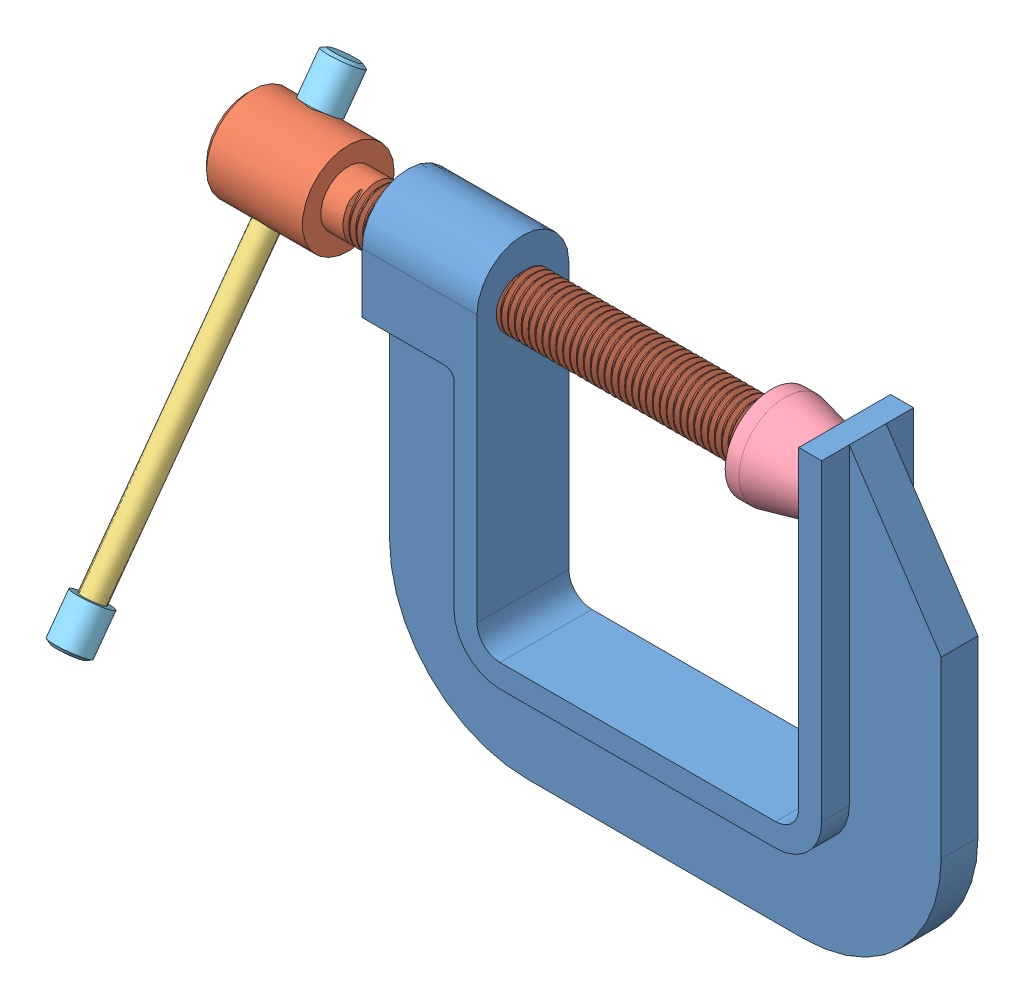
SolidWorks assembly Assem1, configuration Default. Lengths in mm.
Overall size (206.43 104.53 68.23).
6 component instances, 5 part files, 13 mates.
Components (placement in the parent):
- 1-Clamp-1: 1-Clamp [Default] at (98.6392 5.6891 70.0698) size (120.62 98 20)
- 2-Screw-1: 2-Screw [Default] at (62.5202 91.6472 70.0698) x (1 0 0) z (0 0.589813 0.80754) size (206.43 20 20)
- 3-Bar-1: 3-Bar [Default] at (13.6392 27.044 117.2549) x (0 0.80754 -0.589813) z (0.731729 0.402014 0.550415) size (96 5 5)
- 4-Bush-1: 4-Bush [Default] at (117.6392 91.6472 70.0698) size (16 20 20)
- 5-Cap-1: 5-Cap [Default] at (13.6392 106.9905 58.8634) x (0 -0.80754 0.589813) z (0.861072 0.29991 0.410621) size (9 8 8)
- 5-Cap-2: 5-Cap [Default] at (13.6392 24.6214 119.0243) x (0 0.80754 -0.589813) z (0.13914 0.584076 0.799685) size (9 8 8)
Mates (geometry in assembly coordinates):
- Coincident1: coincident: plane of 3-Bar-1 through (13.6392 27.044 117.2549) normal (0 -0.80754 0.589813); plane of 5-Cap-2 through (13.6392 27.044 117.2549) normal (0 0.80754 -0.589813)
- Concentric1: concentric: cylinder of 3-Bar-1 through (13.6392 104.5679 60.6328) axis (0 -0.80754 0.589813) radius 2.5; cylinder of 5-Cap-2 through (13.6392 27.044 117.2549) axis (0 0.80754 -0.589813) radius 2.5
- Coincident3: coincident: plane of 3-Bar-1 through (13.6392 104.5679 60.6328) normal (0 0.80754 -0.589813); plane of 5-Cap-1 through (13.6392 104.5679 60.6328) normal (0 -0.80754 0.589813)
- Concentric2: concentric: cylinder of 3-Bar-1 through (13.6392 104.5679 60.6328) axis (0 -0.80754 0.589813) radius 2.5; cylinder of 5-Cap-1 through (13.6392 104.5679 60.6328) axis (0 -0.80754 0.589813) radius 2.5
- Concentric3: concentric: cylinder of 2-Screw-1 through (-43.2347 91.6472 70.0698) axis (-1 0 0) radius 3; cylinder of 4-Bush-1 through (108.8912 91.6472 70.0698) axis (1 0 0) radius 3.8
- Coincident4: coincident: plane of 2-Screw-1 through (133.6392 94.0698 68.3004) normal (1 0 0); plane of 4-Bush-1 through (133.6392 91.6472 70.0698) normal (1 0 0)
- Coincident5: coincident: axis of 1-Clamp-1 through (63.6392 91.6472 70.0698) axis (-1 0 0); line of 2-Screw-1 through (-43.2347 91.6472 70.0698) axis (1 0 0)
- Coincident7: coincident: plane of 1-Clamp-1 through (133.6392 103.6891 80.0698) normal (-1 0 0); plane of 4-Bush-1 through (133.6392 91.6472 70.0698) normal (1 0 0)
- Concentric4: concentric: cylinder of 2-Screw-1 through (13.6392 83.571 75.9685) axis (0 0.80754 -0.589813) radius 2.75; cylinder of 3-Bar-1 through (13.6392 104.5679 60.6328) axis (0 -0.80754 0.589813) radius 2.5
- Concentric5: concentric: cylinder of 2-Screw-1 through (13.6392 83.571 75.9685) axis (0 0.80754 -0.589813) radius 2.75; cylinder of 3-Bar-1 through (13.6392 104.5679 60.6328) axis (0 -0.80754 0.589813) radius 2.5
- Concentric6: concentric: cylinder of 2-Screw-1 through (13.6392 83.571 75.9685) axis (0 0.80754 -0.589813) radius 2.75; cylinder of 3-Bar-1 through (13.6392 104.5679 60.6328) axis (0 -0.80754 0.589813) radius 2.5
- Perpendicular1: perpendicular: axis of 2-Screw-1 through (25.6392 91.6472 70.0698) axis (-1 0 0); axis of 3-Bar-1 through (13.6392 104.5679 60.6328) axis (0 -0.80754 0.589813)
- Tangent5: tangent: cylinder of 2-Screw-1 through (-43.2347 91.6472 70.0698) axis (-1 0 0) radius 10; plane of 5-Cap-1 through (13.6392 99.7226 64.1717) normal (0 -0.80754 0.589813)
